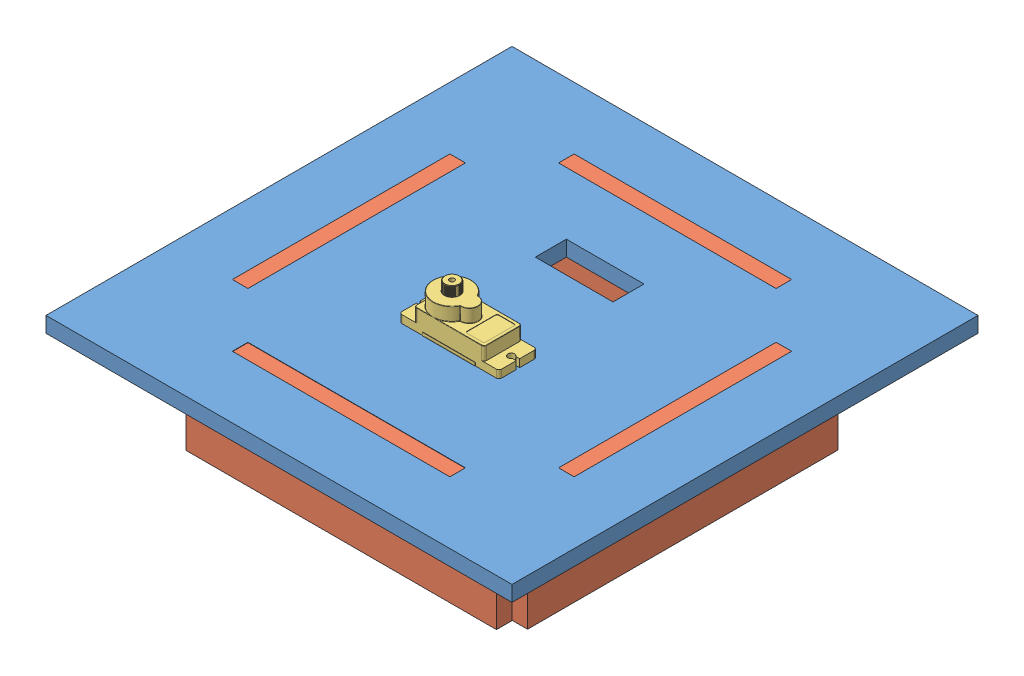
SolidWorks assembly final stand, configuration Default. Lengths in mm.
Overall size (150 49.26 150).
6 component instances, 3 part files, 14 mates.
Components (placement in the parent):
- fial frame-1: fial frame [Default] at (137.3102 58.2125 198.7372) size (150 5 150)
- legs-1: legs [Default] at (7.3102 28.2125 73.7372) size (5 35 100)
- legs-2: legs [Default] at (112.3102 28.2125 73.7372) size (5 35 100)
- legs-3: legs [Default] at (12.3102 28.1057 178.7372) x (0 0 -1) z (1 0 0) size (5 35 100)
- legs-4: legs [Default] at (12.3102 28.2125 73.7372) x (0 0 -1) z (1 0 0) size (5 35 100)
- SG90 - Micro Servo 9g - Tower Pro.1-1: SG90 - Micro Servo 9g - Tower Pro.1 [Peça] at (62.0602 58.0625 137.6372) size (32.1 29.95 12.4)
Mates (geometry in assembly coordinates):
- Coincident6: coincident: plane of assembly; plane of assembly; plane of fial frame-1 through (137.3102 63.2125 198.7372) normal (0 1 0); plane of legs-2 through (117.3102 63.2125 158.7372) normal (0 1 0)
- Coincident7: coincident: plane of assembly; plane of assembly; plane of fial frame-1 through (112.3102 63.2125 88.7372) normal (1 0 0); plane of legs-2 through (112.3102 28.2125 73.7372) normal (-1 0 0)
- Coincident8: coincident: plane of assembly; plane of assembly; plane of fial frame-1 through (117.3102 63.2125 158.7372) normal (0 0 -1); plane of legs-2 through (117.3102 58.2125 158.7372) normal (0 0 1)
- Coincident10: coincident: plane of assembly; plane of assembly; plane of fial frame-1 through (12.3102 63.2125 158.7372) normal (0 0 -1); plane of legs-1 through (12.3102 58.2125 158.7372) normal (0 0 1)
- Coincident11: coincident: plane of assembly; plane of assembly; plane of fial frame-1 through (137.3102 63.2125 198.7372) normal (0 1 0); plane of legs-1 through (12.3102 63.2125 158.7372) normal (0 1 0)
- Coincident12: coincident: plane of assembly; plane of assembly; plane of fial frame-1 through (12.3102 63.2125 88.7372) normal (-1 0 0); plane of legs-1 through (12.3102 28.2125 73.7372) normal (1 0 0)
- Coincident13: coincident: plane of assembly; plane of assembly; plane of fial frame-1 through (97.3102 63.2125 178.7372) normal (-1 0 0); plane of legs-3 through (97.3102 58.1057 173.7372) normal (1 0 0)
- Coincident15: coincident: plane of assembly; plane of assembly; plane of fial frame-1 through (27.3102 63.2125 173.7372) normal (0 0 1); plane of legs-3 through (12.3102 28.1057 173.7372) normal (0 0 -1)
- Coincident16: coincident: plane of assembly; plane of assembly; plane of fial frame-1 through (27.3102 63.2125 68.7372) normal (1 0 0); plane of legs-4 through (27.3102 63.2125 68.7372) normal (-1 0 0)
- Coincident17: coincident: plane of assembly; plane of assembly; plane of fial frame-1 through (27.3102 63.2125 68.7372) normal (0 0 1); plane of legs-4 through (12.3102 28.2125 68.7372) normal (0 0 -1)
- Coincident18: coincident: plane of assembly; plane of assembly; plane of fial frame-1 through (137.3102 63.2125 198.7372) normal (0 1 0); plane of legs-4 through (97.3102 63.2125 68.7372) normal (0 1 0)
- Coincident19: coincident: plane of assembly; plane of assembly; plane of fial frame-1 through (50.8102 63.2125 143.7372) normal (0 0 -1); plane of SG90 - Micro Servo 9g - Tower Pro.1-1 through (46.8602 65.7125 143.7372) normal (0 0 1)
- Coincident20: coincident: plane of assembly; plane of assembly; plane of fial frame-1 through (50.8102 63.2125 131.2372) normal (1 0 0); plane of SG90 - Micro Servo 9g - Tower Pro.1-1 through (50.8102 63.2125 142.8872) normal (-1 0 0)
- Coincident21: coincident: plane of assembly; plane of assembly; plane of fial frame-1 through (137.3102 63.2125 198.7372) normal (0 1 0); plane of SG90 - Micro Servo 9g - Tower Pro.1-1 through (46.8602 63.2125 142.8872) normal (0 -1 0)
